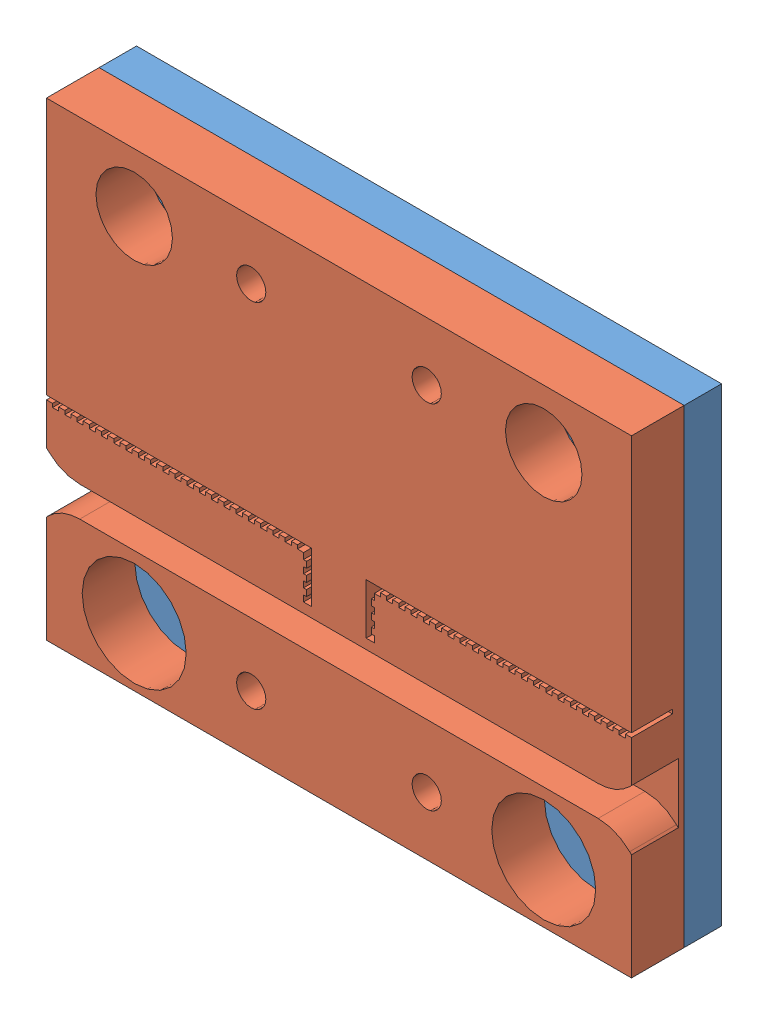
SolidWorks assembly Assem1, configuration Default. Lengths in mm.
Overall size (100 80.26 15.4).
2 component instances, 2 part files, 4 mates.
Components (placement in the parent):
- LaserPlate^CrossBarAssem-1: LaserPlate^CrossBarAssem [Default] at (-54.1545 19.036 -25.4411) size (100 80.26 6.4)
- Part9^Assem1-1: Part9^Assem1 [Default] at (-54.1545 19.036 -19.0411) size (100 80.26 9) (virtual)
Mates (geometry in assembly coordinates):
- InPlace1: in place: plane of LaserPlate^CrossBarAssem-1 through (-54.1545 19.036 -19.0411) normal (0 0 1); plane of ? through (0 0 -19.0411) normal (0 0 1); moOrthogonalPlaneRef_w of LaserPlate^CrossBarAssem-1 through (-54.1545 19.036 -19.0411) normal (0 0 1); plane of ? through (0 0 -19.0411) normal (0 1 0); plane of LaserPlate^CrossBarAssem-1 through (-54.1545 19.036 -19.0411) normal (0 0 1); plane of ? through (0 0 -19.0411) normal (1 0 0); plane of LaserPlate^CrossBarAssem-1 through (-54.1545 19.036 -19.0411) normal (0 0 1); unknown of Part9^Assem1-1
- Coincident1: coincident aligned: plane of LaserPlate^CrossBarAssem-1; plane of Part9^Assem1-1
- Coincident2: coincident aligned: moOrthogonalPlaneRef_w of LaserPlate^CrossBarAssem-1 through (-54.1545 19.036 -19.0411) normal (0 1 0); plane of Part9^Assem1-1 through (-54.1545 19.036 -19.0411) normal (0 1 0)
- Coincident3: coincident anti-aligned: moOrthogonalPlaneRef_w of LaserPlate^CrossBarAssem-1 through (-54.1545 19.036 -19.0411) normal (-1 0 0); plane of Part9^Assem1-1 through (-54.1545 19.036 -19.0411) normal (1 0 0)
